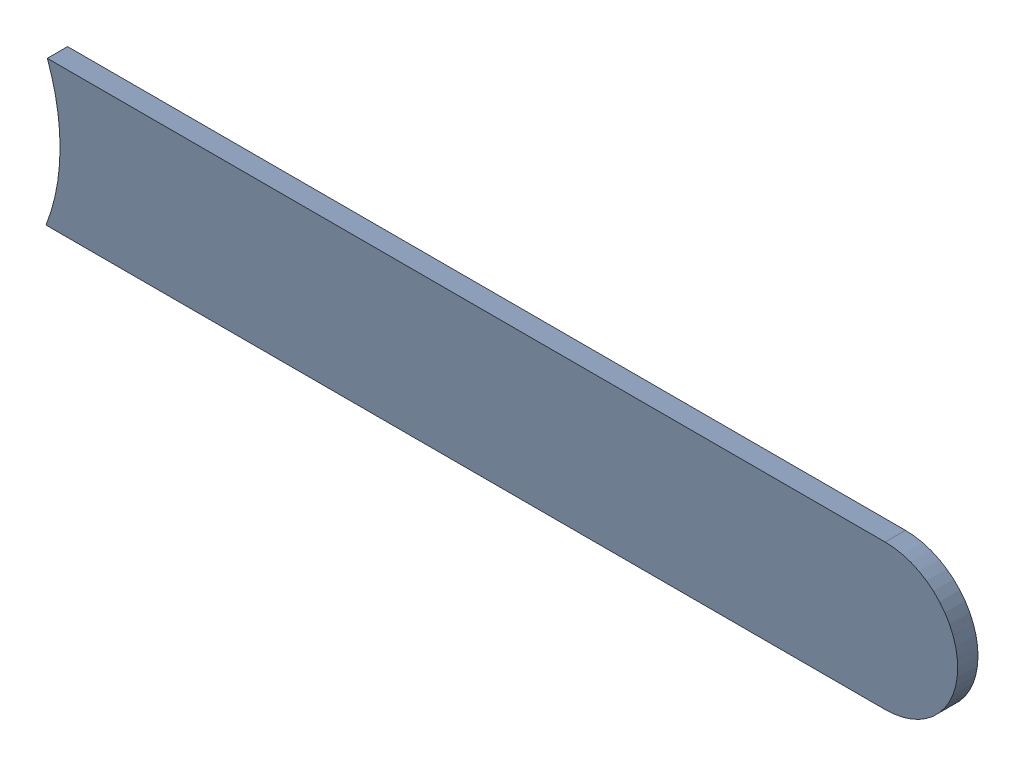
SolidWorks assembly Track (17.203mm,58.097mm)(19mm,58.097mm) on Top Layer, configuration Predeterminado. Lengths in mm.
Overall size (1.6 0.25 0.04).
2 component instances, 1 part files, 0 mates.
Components (placement in the parent):
- Track (17.203mm,58.097mm)(19mm,58.097mm) on Top Layer-1-1: Track (17.203mm,58.097mm)(19mm,58.097mm) on Top Layer-1 [Predeterminado] at (-68.317 -44.187 -0.0457) size (1.6 0.25 0.04)
  - Track (17.203mm,58.097mm)(19mm,58.097mm) on Top Layer-Part-1-1: Track (17.203mm,58.097mm)(19mm,58.097mm) on Top Layer-Part-1 [Predeterminado] at origin size (1.6 0.25 0.04)
